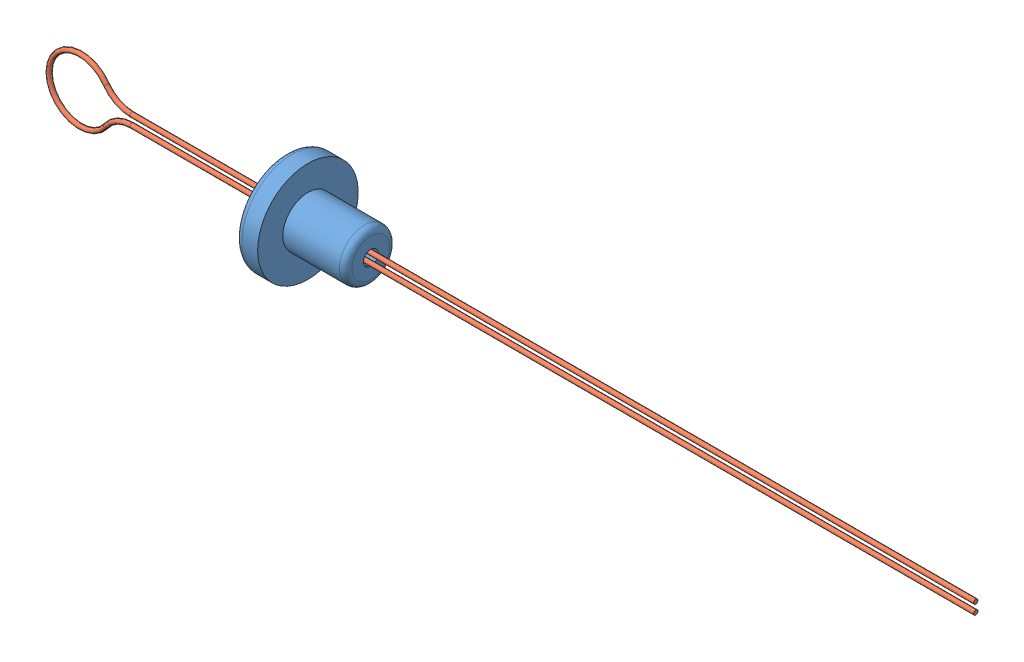
SolidWorks assembly vareta de oleo, configuration Valor predeterminado. Lengths in mm.
Overall size (295.59 32 32).
2 component instances, 2 part files, 2 mates.
Components (placement in the parent):
- Peça 2-1: Peça 2 [Valor predeterminado] at (28.8886 2.1661 0) size (27 32 32)
- Peça 1 - vareta do oleo-1: Peça 1 - vareta do oleo [Valor predeterminado] at (-84 2.1661 0) size (295.59 21.4 1.4)
Mates (geometry in assembly coordinates):
- Concêntrico1: concentric anti-aligned: circle of Peça 2-1; circle of Peça 1 - vareta do oleo-1
- Coincidente1: coincident anti-aligned: plane of Peça 2-1 through (-18.6404 4.5161 0) normal (-1 0 0); circle of Peça 1 - vareta do oleo-1
